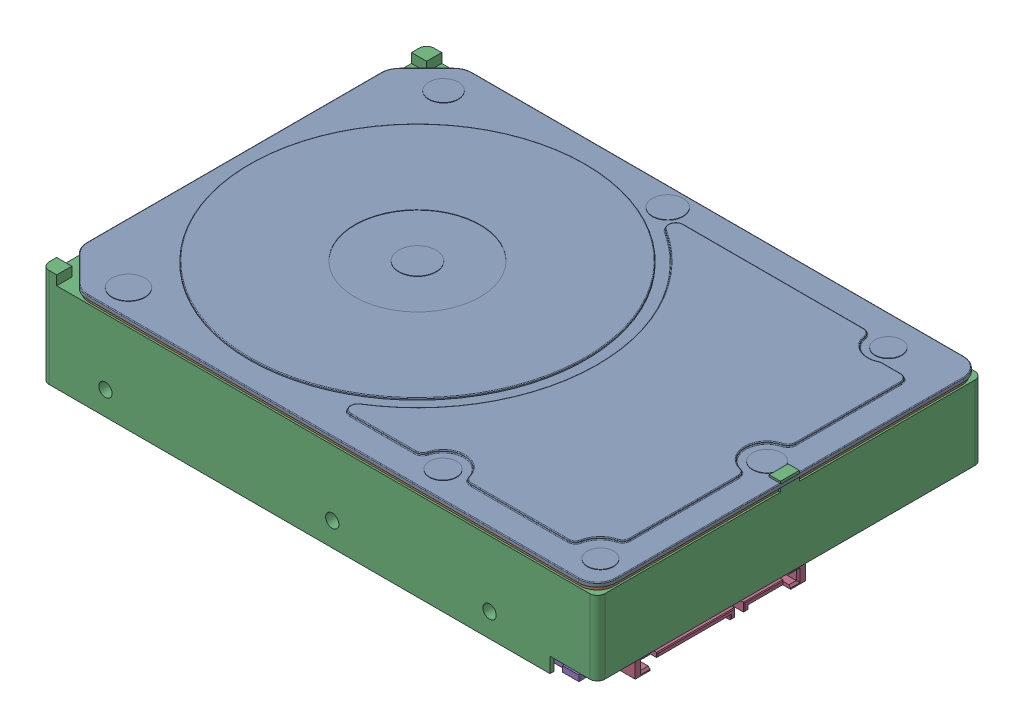
SolidWorks assembly 3.5in generic hdd full assembly, configuration Default. Lengths in mm.
Overall size (146.99 26.11 101.85).
5 component instances, 5 part files, 12 mates.
Components (placement in the parent):
- steel cover-1: steel cover [Default] at (-84.7659 79.4828 -9.7792) size (146.99 1.5 101.85)
- SEAL-1: SEAL [Default] at (-84.7659 79.4828 -9.7792) x (-1 0 0) z (0 -1 0) size (145.99 100.85 1)
- Base-1: Base [Default] at (-84.7659 54.8728 -9.7792) size (146.99 26.11 101.85)
- Sata connector-1: Sata connector [Default] at (-14.6209 58.8728 8.6458) x (0 0 1) z (1 0 0) size (45 4 6.7)
- pcb-1: pcb [Default] at (-84.9521 56.3728 -10.2792) x (-1 0 0) z (0 -1 0) size (75.48 98.85 1.5)
Mates (geometry in assembly coordinates):
- InPlace1: in place: plane of steel cover-1 through (-146.1898 79.4828 36.1458) normal (0 -1 0); plane of ? through (0 79.4828 0) normal (0 -1 0); moOrthogonalPlaneRef_w of steel cover-1 through (-146.1898 79.4828 36.1458) normal (0 -1 0); plane of ? through (0 79.4828 0) normal (0 0 -1); plane of steel cover-1 through (-146.1898 79.4828 36.1458) normal (0 -1 0); plane of ? through (0 79.4828 0) normal (-1 0 0); plane of steel cover-1 through (-146.1898 79.4828 36.1458) normal (0 -1 0); unknown of SEAL-1
- Coincident1: coincident aligned: plane of steel cover-1; plane of SEAL-1
- Coincident2: coincident aligned: moOrthogonalPlaneRef_w of steel cover-1 through (-84.7659 79.4828 -9.7792) normal (0 0 -1); plane of Part52^Assem9-1 through (-84.7659 79.4828 -9.7792) normal (0 0 -1)
- Coincident3: coincident anti-aligned: moOrthogonalPlaneRef_w of steel cover-1 through (-84.7659 79.4828 -9.7792) normal (1 0 0); plane of Part52^Assem9-1 through (-84.7659 79.4828 -9.7792) normal (-1 0 0)
- Coincident4: coincident aligned: plane of steel cover-1 through (-109.7659 80.9828 -9.7792) normal (0 1 0); plane of Base-1 through (-84.7659 80.9828 -9.7792) normal (0 1 0)
- Coincident5: coincident aligned: plane of steel cover-1 through (-146.1898 80.4828 -60.7042) normal (0 0 -1); plane of Base-1 through (-158.2609 80.9828 -60.7042) normal (0 0 -1)
- Coincident6: coincident aligned: plane of steel cover-1 through (-11.2709 80.4828 36.1458) normal (1 0 0); plane of Base-1 through (-11.2709 80.9828 41.1458) normal (1 0 0)
- Coincident7: coincident anti-aligned: plane of Base-1 through (-52.5509 58.8728 37.8458) normal (0 -1 0); plane of Sata connector-1 through (-14.6209 58.8728 8.6458) normal (0 1 0)
- Coincident8: coincident aligned: plane of Base-1 through (-11.2709 80.9828 41.1458) normal (1 0 0); plane of Sata connector-1 through (-11.2709 54.8728 -13.8542) normal (1 0 0)
- Distance1: distance = 10 mm aligned: plane of Sata connector-1 through (-11.2709 54.8728 31.1458) normal (0 0 1); plane of Base-1 through (-158.2609 80.9828 41.1458) normal (0 0 1)
- Coincident13: coincident aligned: plane of Base-1 through (-84.7659 54.8728 -9.7792) normal (0 -1 0); plane of pcb-1 through (-52.7371 54.8728 37.3458) normal (0 -1 0)
- Distance2: distance = 1 mm anti-aligned: plane of pcb-1 through (-92.9345 54.8728 -58.7042) normal (0 0 -1); plane of Base-1 through (-84.7659 56.8728 -59.7042) normal (0 0 1)
